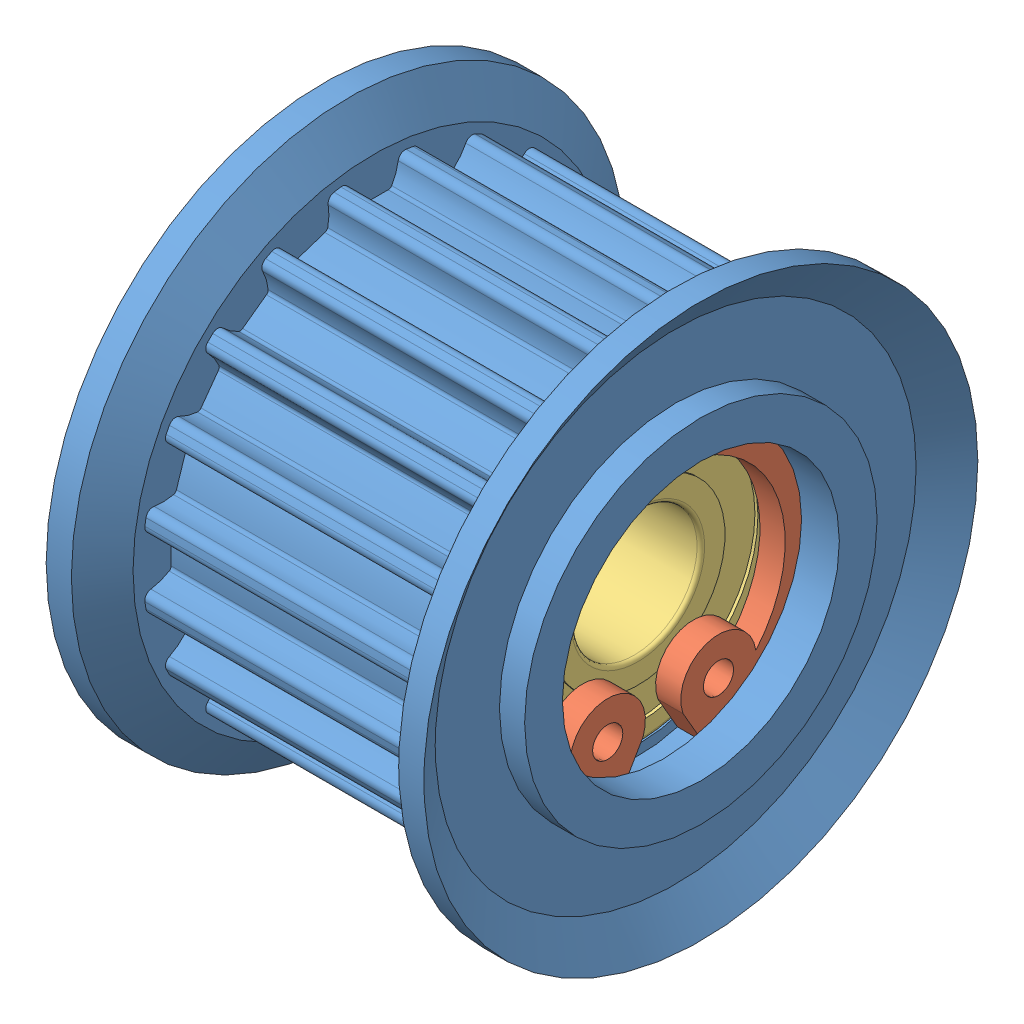
SolidWorks assembly AHTF20S3M100, configuration Default. Lengths in mm.
Overall size (15 22 22).
4 component instances, 3 part files, 0 mates.
Components (placement in the parent):
- AHTF20S3M100flanged_idlers-1: AHTF20S3M100flanged_idlers [Default] at origin size (15 22 22)
- RTWS11-1: RTWS11 [Default] at (5.5 0 0) size (1 11.59 11.8)
- B685ZZ-1: B685ZZ [Default] x (-1 0 0) z (0 0 1) size (5 11 11)
- B685ZZ-2: B685ZZ [Default] at origin size (5 11 11)
